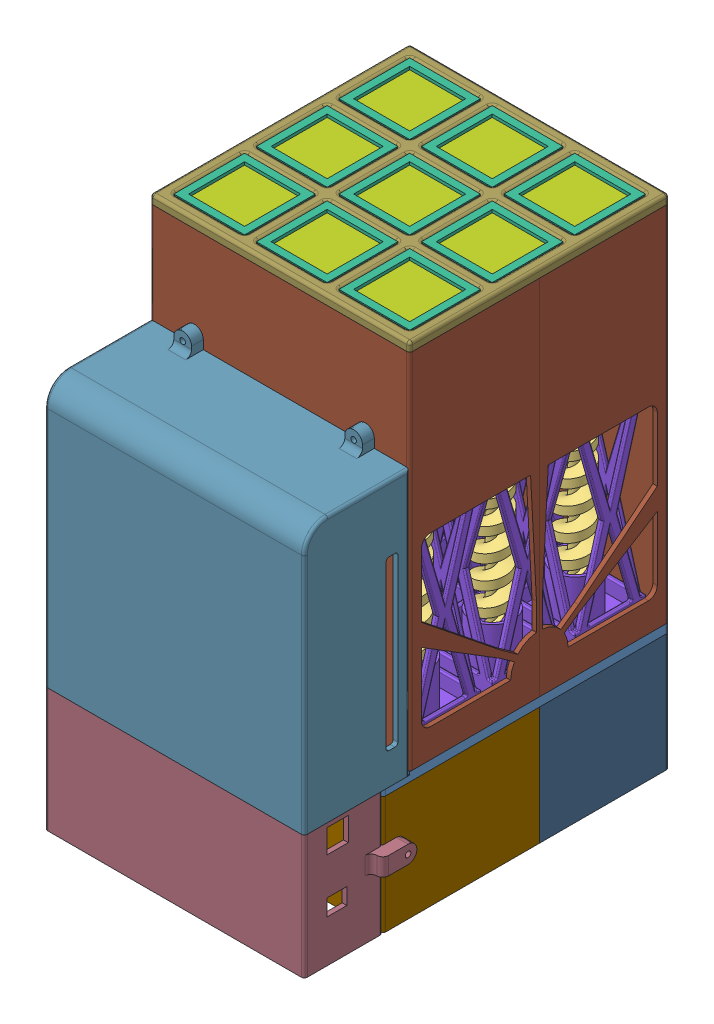
SolidWorks assembly POC_FINAL, configuration Default. Lengths in mm.
Overall size (152.4 268.26 196.44).
80 component instances, 14 part files, 29 mates.
Components (placement in the parent):
- Baseplate-1: Baseplate [Default] at (-8.701 90.6472 151.7236) size (139.7 11.11 154.21)
- StepMotor28BYJ-1: StepMotor28BYJ [Default] at (80.199 71.6472 168.6136) size (42 29 31)
- StepMotor28BYJ-2: StepMotor28BYJ [Default] at (80.199 71.6472 124.1636) size (42 29 31)
- StepMotor28BYJ-3: StepMotor28BYJ [Default] at (80.199 71.6472 79.7136) size (42 29 31)
- StepMotor28BYJ-4: StepMotor28BYJ [Default] at (35.749 71.6472 168.6136) size (42 29 31)
- StepMotor28BYJ-5: StepMotor28BYJ [Default] at (35.749 71.6472 124.1636) size (42 29 31)
- StepMotor28BYJ-6: StepMotor28BYJ [Default] at (35.749 71.6472 79.7136) size (42 29 31)
- StepMotor28BYJ-7: StepMotor28BYJ [Default] at (-8.701 71.6472 168.6136) size (42 29 31)
- StepMotor28BYJ-8: StepMotor28BYJ [Default] at (-8.701 71.6472 124.1636) size (42 29 31)
- StepMotor28BYJ-9: StepMotor28BYJ [Default] at (-8.701 71.6472 79.7136) size (42 29 31)
- Power_Screw-1: Power_Screw [Default] at (80.199 101.4409 71.7136) size (18.54 113.3 18.26)
- Power_Screw-2: Power_Screw [Default] at (80.199 101.4409 116.1636) size (18.54 113.3 18.26)
- Power_Screw-3: Power_Screw [Default] at (80.199 101.4409 160.6136) size (18.54 113.3 18.26)
- Power_Screw-4: Power_Screw [Default] at (35.749 101.4409 71.7136) size (18.54 113.3 18.26)
- Power_Screw-5: Power_Screw [Default] at (35.749 101.4409 116.1636) size (18.54 113.3 18.26)
- Power_Screw-6: Power_Screw [Default] at (35.749 101.4409 160.6136) size (18.54 113.3 18.26)
- Power_Screw-7: Power_Screw [Default] at (-8.701 101.4409 71.7136) size (18.54 113.3 18.26)
- Power_Screw-8: Power_Screw [Default] at (-8.701 101.4409 116.1636) size (18.54 113.3 18.26)
- Power_Screw-9: Power_Screw [Default] at (-8.701 101.4409 160.6136) size (18.54 113.3 18.26)
- Pin_Assembly-10: Pin_Assembly [Default] at (46.7199 143.9417 -3.9639) size (41.27 200.82 41.28)
  - Lower_Pin_Upper-1: Lower_Pin_Upper [Default] at (33.479 -32.182 75.6775) size (38.1 7.81 38.1)
  - Board_Plate-1: Board_Plate [Default] at (33.479 69.291 75.6775) x (-1 0 0) z (0 0 -1) size (38.1 6.86 38.1)
  - Upper_Pin-1: Upper_Pin [Default] at (33.479 70.8785 75.6775) size (41.27 92.87 41.27)
  - Pin_Surface-1: Pin_Surface [Default] at (33.5584 76.5173 75.7569) size (34.54 72.15 34.54)
  - Lower_Pin_Lower_V3-1: Lower_Pin_Lower_V3 [Default] at (33.479 -44.882 75.6775) size (38.1 107.68 38.1)
- Pin_Assembly-11: Pin_Assembly [Default] at (2.2699 143.9417 -3.9639) size (41.27 200.82 41.28)
  - Lower_Pin_Upper-1: Lower_Pin_Upper [Default] at (33.479 -32.182 75.6775) size (38.1 7.81 38.1)
  - Board_Plate-1: Board_Plate [Default] at (33.479 69.291 75.6775) x (-1 0 0) z (0 0 -1) size (38.1 6.86 38.1)
  - Upper_Pin-1: Upper_Pin [Default] at (33.479 70.8785 75.6775) size (41.27 92.87 41.27)
  - Pin_Surface-1: Pin_Surface [Default] at (33.5584 76.5173 75.7569) size (34.54 72.15 34.54)
  - Lower_Pin_Lower_V3-1: Lower_Pin_Lower_V3 [Default] at (33.479 -44.882 75.6775) size (38.1 107.68 38.1)
- Pin_Assembly-12: Pin_Assembly [Default] at (-42.1801 143.9417 -3.9639) size (41.27 200.82 41.28)
  - Lower_Pin_Upper-1: Lower_Pin_Upper [Default] at (33.479 -32.182 75.6775) size (38.1 7.81 38.1)
  - Board_Plate-1: Board_Plate [Default] at (33.479 69.291 75.6775) x (-1 0 0) z (0 0 -1) size (38.1 6.86 38.1)
  - Upper_Pin-1: Upper_Pin [Default] at (33.479 70.8785 75.6775) size (41.27 92.87 41.27)
  - Pin_Surface-1: Pin_Surface [Default] at (33.5584 76.5173 75.7569) size (34.54 72.15 34.54)
  - Lower_Pin_Lower_V3-1: Lower_Pin_Lower_V3 [Default] at (33.479 -44.882 75.6775) size (38.1 107.68 38.1)
- Pin_Assembly-13: Pin_Assembly [Default] at (46.7199 143.9417 40.4861) size (41.27 200.82 41.28)
  - Lower_Pin_Upper-1: Lower_Pin_Upper [Default] at (33.479 -32.182 75.6775) size (38.1 7.81 38.1)
  - Board_Plate-1: Board_Plate [Default] at (33.479 69.291 75.6775) x (-1 0 0) z (0 0 -1) size (38.1 6.86 38.1)
  - Upper_Pin-1: Upper_Pin [Default] at (33.479 70.8785 75.6775) size (41.27 92.87 41.27)
  - Pin_Surface-1: Pin_Surface [Default] at (33.5584 76.5173 75.7569) size (34.54 72.15 34.54)
  - Lower_Pin_Lower_V3-1: Lower_Pin_Lower_V3 [Default] at (33.479 -44.882 75.6775) size (38.1 107.68 38.1)
- Pin_Assembly-14: Pin_Assembly [Default] at (2.2699 143.9417 40.4861) size (41.27 200.82 41.28)
  - Lower_Pin_Upper-1: Lower_Pin_Upper [Default] at (33.479 -32.182 75.6775) size (38.1 7.81 38.1)
  - Board_Plate-1: Board_Plate [Default] at (33.479 69.291 75.6775) x (-1 0 0) z (0 0 -1) size (38.1 6.86 38.1)
  - Upper_Pin-1: Upper_Pin [Default] at (33.479 70.8785 75.6775) size (41.27 92.87 41.27)
  - Pin_Surface-1: Pin_Surface [Default] at (33.5584 76.5173 75.7569) size (34.54 72.15 34.54)
  - Lower_Pin_Lower_V3-1: Lower_Pin_Lower_V3 [Default] at (33.479 -44.882 75.6775) size (38.1 107.68 38.1)
- Pin_Assembly-15: Pin_Assembly [Default] at (-42.1801 143.9417 40.4861) size (41.27 200.82 41.28)
  - Lower_Pin_Upper-1: Lower_Pin_Upper [Default] at (33.479 -32.182 75.6775) size (38.1 7.81 38.1)
  - Board_Plate-1: Board_Plate [Default] at (33.479 69.291 75.6775) x (-1 0 0) z (0 0 -1) size (38.1 6.86 38.1)
  - Upper_Pin-1: Upper_Pin [Default] at (33.479 70.8785 75.6775) size (41.27 92.87 41.27)
  - Pin_Surface-1: Pin_Surface [Default] at (33.5584 76.5173 75.7569) size (34.54 72.15 34.54)
  - Lower_Pin_Lower_V3-1: Lower_Pin_Lower_V3 [Default] at (33.479 -44.882 75.6775) size (38.1 107.68 38.1)
- Pin_Assembly-16: Pin_Assembly [Default] at (46.7199 143.9417 84.9361) size (41.27 200.82 41.28)
  - Lower_Pin_Upper-1: Lower_Pin_Upper [Default] at (33.479 -32.182 75.6775) size (38.1 7.81 38.1)
  - Board_Plate-1: Board_Plate [Default] at (33.479 69.291 75.6775) x (-1 0 0) z (0 0 -1) size (38.1 6.86 38.1)
  - Upper_Pin-1: Upper_Pin [Default] at (33.479 70.8785 75.6775) size (41.27 92.87 41.27)
  - Pin_Surface-1: Pin_Surface [Default] at (33.5584 76.5173 75.7569) size (34.54 72.15 34.54)
  - Lower_Pin_Lower_V3-1: Lower_Pin_Lower_V3 [Default] at (33.479 -44.882 75.6775) size (38.1 107.68 38.1)
- Pin_Assembly-17: Pin_Assembly [Default] at (2.2699 143.9417 84.9361) size (41.27 200.82 41.28)
  - Lower_Pin_Upper-1: Lower_Pin_Upper [Default] at (33.479 -32.182 75.6775) size (38.1 7.81 38.1)
  - Board_Plate-1: Board_Plate [Default] at (33.479 69.291 75.6775) x (-1 0 0) z (0 0 -1) size (38.1 6.86 38.1)
  - Upper_Pin-1: Upper_Pin [Default] at (33.479 70.8785 75.6775) size (41.27 92.87 41.27)
  - Pin_Surface-1: Pin_Surface [Default] at (33.5584 76.5173 75.7569) size (34.54 72.15 34.54)
  - Lower_Pin_Lower_V3-1: Lower_Pin_Lower_V3 [Default] at (33.479 -44.882 75.6775) size (38.1 107.68 38.1)
- Pin_Assembly-18: Pin_Assembly [Default] at (-42.1801 143.9417 84.9361) size (41.27 200.82 41.28)
  - Lower_Pin_Upper-1: Lower_Pin_Upper [Default] at (33.479 -32.182 75.6775) size (38.1 7.81 38.1)
  - Board_Plate-1: Board_Plate [Default] at (33.479 69.291 75.6775) x (-1 0 0) z (0 0 -1) size (38.1 6.86 38.1)
  - Upper_Pin-1: Upper_Pin [Default] at (33.479 70.8785 75.6775) size (41.27 92.87 41.27)
  - Pin_Surface-1: Pin_Surface [Default] at (33.5584 76.5173 75.7569) size (34.54 72.15 34.54)
  - Lower_Pin_Lower_V3-1: Lower_Pin_Lower_V3 [Default] at (33.479 -44.882 75.6775) size (38.1 107.68 38.1)
- Housing_Base_Female-1: Housing_Base_Female [Default] at (35.7484 27.1472 123.4178) size (139.7 63.5 84.36)
- Housing_Base_Male-1: Housing_Base_Male [Default] at (35.7484 27.1472 123.4178) x (-1 0 0) z (0 0 -1) size (139.7 63.5 73.03)
- Housing_Pin_Half-1: Housing_Pin_Half [Default] at (35.7484 95.4097 116.1636) x (0 0 1) z (-1 0 0) size (69.85 196.83 139.7)
- Housing_Pin_Half-2: Housing_Pin_Half [Default] at (35.7484 95.4097 116.1636) x (0 0 -1) z (1 0 0) size (69.85 196.83 139.7)
- Housing_Pin_Roof-2: Housing_Pin_Roof [Default] at (35.7484 295.4097 116.1636) x (-1 0 0) z (0 0 1) size (139.7 7.94 139.7)
- Electronics_Mounting_Plate_Lower-1: Electronics_Mounting_Plate_Lower [Default] at (35.7484 131.9222 242.7495) x (-1 0 0) z (0 0 -1) size (152.4 66.68 54.29)
- Electronics_Mounting_Plate_Upper-1: Electronics_Mounting_Plate_Upper [Default] at (35.7484 131.9222 242.7495) x (-1 0 0) z (0 0 -1) size (139.7 152.4 56.74)
Mates (geometry in assembly coordinates):
- Parallel1: parallel aligned: plane of Baseplate-1 through (-8.701 93.8222 200.522) normal (0 0 1); plane of StepMotor28BYJ-1 through (72.949 90.6472 185.6136) normal (0 0 1)
- Concentric1: concentric aligned: cylinder of Baseplate-1 through (80.199 93.8222 160.6136) axis (0 -1 0) radius 5.08; cylinder of StepMotor28BYJ-1 through (80.199 92.1472 160.6136) axis (0 -1 0) radius 4.5
- Coincident2: coincident anti-aligned: plane of Baseplate-1 through (-8.701 90.6472 151.7236) normal (0 -1 0); plane of StepMotor28BYJ-1 through (80.199 90.6472 168.6136) normal (0 1 0)
- Coincident3: coincident anti-aligned: plane of StepMotor28BYJ-3 through (80.199 100.6472 71.7136) normal (0 1 0); plane of Power_Screw-1 through (80.199 100.6472 71.7136) normal (0 -1 0)
- Concentric2: concentric aligned: cylinder of StepMotor28BYJ-3 through (80.199 100.6472 71.7136) axis (0 -1 0) radius 2.5; cylinder of Power_Screw-1 through (80.199 100.6472 71.7136) axis (0 -1 0) radius 2.5
- Parallel2: parallel aligned: plane of Baseplate-1 through (-34.1016 93.8222 151.7236) normal (-1 0 0); plane of Pin_Assembly-10/Lower_Pin_Lower_V3-1 through (61.149 200.6597 71.7136) normal (-1 0 0)
- Concentric3: concentric aligned: cylinder of Power_Screw-1 through (80.199 110.9659 71.7136) axis (0 -1 0) radius 9.1281; cylinder of Pin_Assembly-10/Lower_Pin_Lower_V3-1 through (80.199 124.4597 71.7136) axis (0 -1 0) radius 11.5094
- Coincident5: coincident anti-aligned: plane of Power_Screw-1 through (80.199 203.0409 71.7136) normal (0 1 0); plane of Pin_Assembly-10/Lower_Pin_Upper-1 through (80.199 203.0409 71.7136) normal (0 -1 0)
- Coincident6: coincident anti-aligned: plane of Baseplate-1 through (-8.701 90.6472 151.7236) normal (0 -1 0); plane of Housing_Base_Female-1 through (35.7484 90.6472 123.4178) normal (0 1 0)
- Coincident7: coincident aligned: plane of Baseplate-1 through (-34.1016 93.8222 151.7236) normal (-1 0 0); plane of Housing_Base_Female-1 through (-34.1016 33.4972 200.522) normal (-1 0 0)
- Coincident8: coincident aligned: plane of Baseplate-1 through (-8.701 93.8222 200.522) normal (0 0 1); plane of Housing_Base_Female-1 through (-34.1016 33.4972 200.522) normal (0 0 1)
- Coincident9: coincident aligned: plane of Baseplate-1 through (-8.701 93.8222 46.3136) normal (0 0 -1); plane of Housing_Base_Male-1 through (105.5984 33.4972 46.3136) normal (0 0 -1)
- Coincident10: coincident aligned: plane of Baseplate-1 through (-34.1016 93.8222 151.7236) normal (-1 0 0); plane of Housing_Base_Male-1 through (-34.1016 33.4972 46.3136) normal (-1 0 0)
- Coincident11: coincident anti-aligned: plane of Baseplate-1 through (-8.701 90.6472 151.7236) normal (0 -1 0); plane of Housing_Base_Male-1 through (35.7484 90.6472 123.4178) normal (0 1 0)
- Coincident15: coincident aligned: plane of Baseplate-1 through (-34.1016 95.4097 186.0136) normal (0 0 1); plane of Housing_Pin_Half-1 through (-34.1016 290.6472 186.0136) normal (0 0 1)
- Coincident16: coincident aligned: plane of Housing_Base_Female-1 through (105.5984 33.4972 200.522) normal (1 0 0); plane of Housing_Pin_Half-1 through (105.5984 290.6472 46.3136) normal (1 0 0)
- Coincident17: coincident anti-aligned: plane of Baseplate-1 through (-8.701 95.4097 151.7236) normal (0 1 0); plane of Housing_Pin_Half-1 through (35.7484 95.4097 116.1636) normal (0 -1 0)
- Coincident18: coincident aligned: plane of Housing_Base_Male-1 through (105.5984 33.4972 46.3136) normal (0 0 -1); plane of Housing_Pin_Half-2 through (105.5984 290.6472 46.3136) normal (0 0 -1)
- Coincident19: coincident aligned: plane of Housing_Base_Male-1 through (105.5984 33.4972 46.3136) normal (1 0 0); plane of Housing_Pin_Half-2 through (105.5984 290.6472 186.0136) normal (1 0 0)
- Coincident20: coincident anti-aligned: plane of Baseplate-1 through (-8.701 95.4097 151.7236) normal (0 1 0); plane of Housing_Pin_Half-2 through (35.7484 95.4097 116.1636) normal (0 -1 0)
- Coincident24: coincident anti-aligned: plane of Housing_Pin_Half-1 through (35.7484 290.6472 116.1636) normal (0 1 0); plane of Housing_Pin_Roof-2 through (35.7484 290.6472 116.1636) normal (0 -1 0)
- Coincident25: coincident aligned: plane of Housing_Pin_Half-2 through (105.5984 290.6472 186.0136) normal (1 0 0); plane of Housing_Pin_Roof-2 through (105.5984 290.6472 186.0136) normal (1 0 0)
- Coincident26: coincident aligned: plane of Housing_Pin_Half-1 through (-34.1016 290.6472 186.0136) normal (0 0 1); plane of Housing_Pin_Roof-2 through (105.5984 290.6472 186.0136) normal (0 0 1)
- Coincident27: coincident aligned: plane of Housing_Base_Female-1 through (35.7484 27.1472 123.4178) normal (0 -1 0); plane of Electronics_Mounting_Plate_Lower-1 through (105.5984 27.1472 240.2095) normal (0 -1 0)
- Coincident28: coincident aligned: plane of Housing_Base_Female-1 through (-34.1016 33.4972 200.522) normal (-1 0 0); plane of Electronics_Mounting_Plate_Lower-1 through (-34.1016 27.1472 240.2095) normal (-1 0 0)
- Coincident29: coincident anti-aligned: plane of Housing_Base_Female-1 through (-34.1016 33.4972 200.522) normal (0 0 1); plane of Electronics_Mounting_Plate_Lower-1 through (35.7484 131.9222 200.522) normal (0 0 -1)
- Coincident30: coincident anti-aligned: plane of Housing_Pin_Half-1 through (-34.1016 290.6472 186.0136) normal (0 0 1); plane of Electronics_Mounting_Plate_Upper-1 through (35.7484 131.9222 186.0136) normal (0 0 -1)
- Coincident31: coincident aligned: plane of Housing_Pin_Half-1 through (105.5984 290.6472 46.3136) normal (1 0 0); plane of Electronics_Mounting_Plate_Upper-1 through (105.5984 27.1472 240.2095) normal (1 0 0)
- Coincident32: coincident anti-aligned: plane of Electronics_Mounting_Plate_Lower-1 through (105.5984 93.8222 251.322) normal (0 1 0); plane of Electronics_Mounting_Plate_Upper-1 through (35.7484 93.8222 186.0136) normal (0 -1 0)
